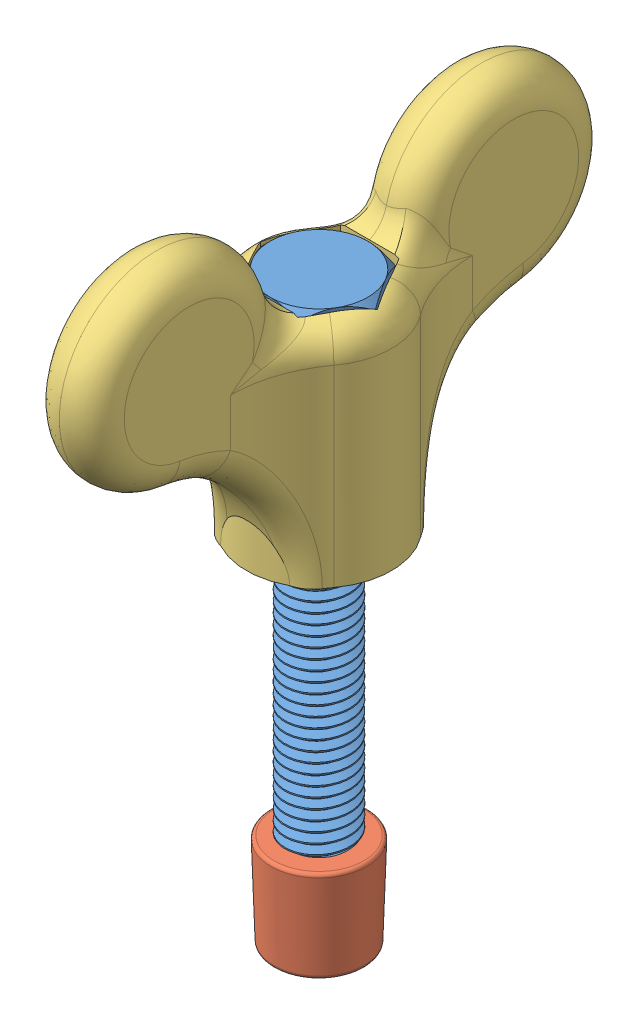
SolidWorks assembly Knob, configuration Default. Lengths in mm.
Overall size (28.4 133.19 101.6).
3 component instances, 3 part files, 4 mates.
Components (placement in the parent):
- 91309A728_Low-Strength Zinc-Plated Steel Hex Head Screw-1: 91309A728_Low-Strength Zinc-Plated Steel Hex Head Screw [91309A728] at (0 114.1412 0) x (0 0 1) z (0 1 0) size (19.05 24.19 111.48)
- Cap Knob Base-2: Cap Knob Base [Default] at origin size (18.76 18.9 18.76)
- Knob handle-1: Knob handle [Default] at origin size (28.4 63.04 101.6)
Mates (geometry in assembly coordinates):
- Coincident1: coordinate: point of Cap Knob Base-2
- Distance1: distance = 3.81 mm aligned: plane of 91309A728_Low-Strength Zinc-Plated Steel Hex Head Screw-1 through (0 3.81 0) normal (0 -1 0); plane of Cap Knob Base-2 through (0 0 0) normal (0 -1 0)
- Concentric1: concentric aligned: circle of 91309A728_Low-Strength Zinc-Plated Steel Hex Head Screw-1; circle of Cap Knob Base-2
- Coincident3: coincident aligned: plane of 91309A728_Low-Strength Zinc-Plated Steel Hex Head Screw-1 through (0 114.1412 0) normal (0 0 1)
